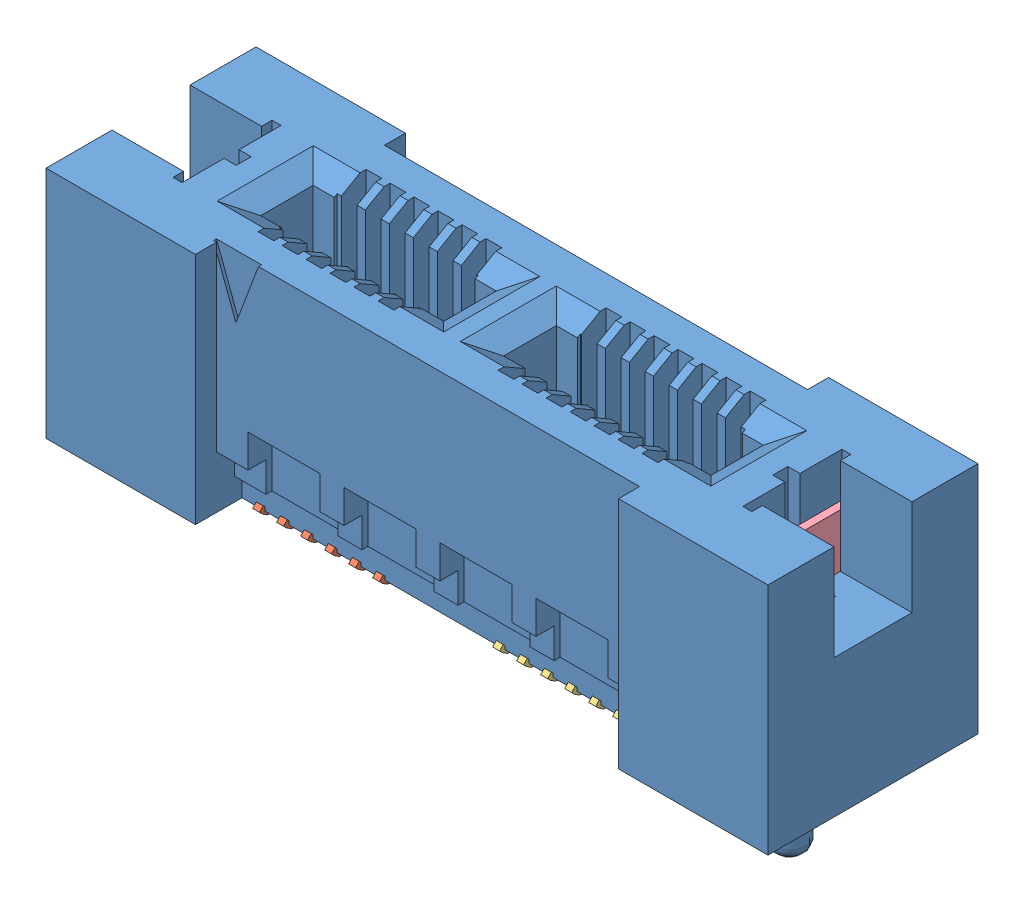
SolidWorks assembly HSEC8_113_01_L_DV_A_L2, configuration Default. Lengths in mm.
Overall size (24.06 9.3 7).
5 component instances, 4 part files, 0 mates.
Components (placement in the parent):
- _HSEC8_113_01_L_DV_A_L2ter_2-1: _HSEC8_113_01_L_DV_A_L2ter_2 [Default] at origin size (24.06 9.3 7)
- _C_188_02_Pin_6_01_4-1: _C_188_02_Pin_6_01_4 [Default] at (-6.4 -0.183 0) x (0 0 1) z (-1 0 0) size (4.26 5.75 4.58)
- _C_188_02_Pin_7_01_6-1: _C_188_02_Pin_7_01_6 [Default] at (1.6 -0.183 0) x (0 0 1) z (-1 0 0) size (4.26 5.75 5.38)
- _WT_25_09_Latching_Option_L2_8-1: _WT_25_09_Latching_Option_L2_8 [Default] at (-9.495 6.355 0) x (0 0 -1) z (1 0 0) size (3.3 7.84 0.25)
- _WT_25_09_Latching_Option_L2_8-2: _WT_25_09_Latching_Option_L2_8 [Default] at (9.495 6.355 0) x (0 0 -1) z (1 0 0) size (3.3 7.84 0.25)
